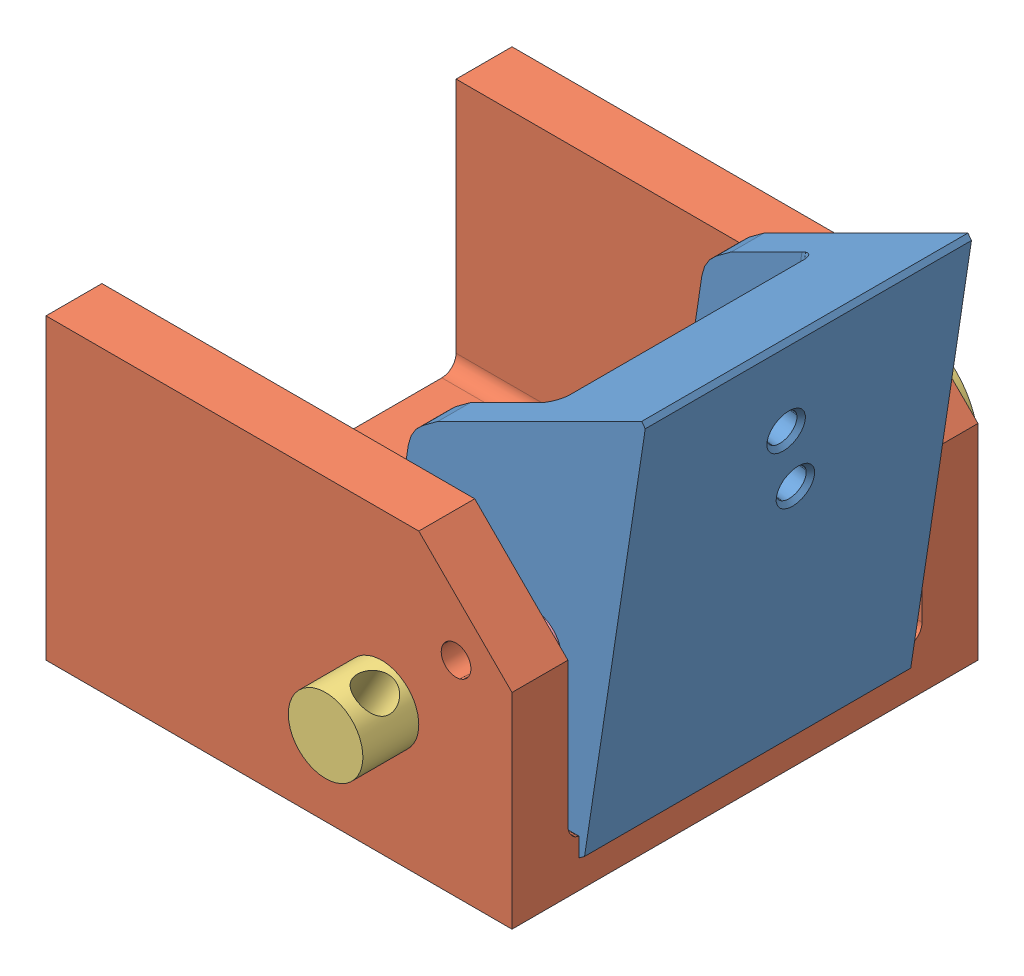
SolidWorks assembly Assem2, configuration Default. Lengths in mm.
Overall size (28.58 25.17 31).
7 component instances, 5 part files, 9 mates.
Components (placement in the parent):
- Swing piece better redesign v2-1: Swing piece better redesign v2 [Default] at (10.5166 16.001 11.8718) x (0.988728 -0.14972 0) z (0 0 1) size (11.5 22.34 17.5)
- Base better redesign-1: Base better redesign [Default] at (1.9122 2.865 20.4718) x (1 0 0) z (0 -1 0) size (25 25 16)
- Hinge mcmaster 4mm-1: Hinge mcmaster 4mm [93217A290] at (7.4122 7.365 129.9718) x (0.866515 -0.49915 0) z (0 0 1) size (8 8 31)
- Pin mcmaster_v2-1: Pin mcmaster_v2 [98378A149] at (11.966 10.7211 -18.0282) x (-0.894491 0.447087 0) z (0 0 -1) size (3 3 7)
- 9271K88_Torsion Spring-1: 9271K88_Torsion Spring [9271K88] at (7.691 7.499 23.983) x (0.159653 -0.022827 -0.986909) z (-0.95932 -0.239394 -0.149653) size (4.03 5.49 38.1) (hidden)
- 9271K88_Torsion Spring-3: 9271K88_Torsion Spring [9271K88] at (7.1421 7.2576 15.5875) x (-0.070231 -0.093274 -0.99316) z (-0.995192 0.074684 0.06336) size (4.03 5.49 38.1) (hidden)
- Pin mcmaster_v2-3: Pin mcmaster_v2 [98378A149] at (11.966 10.7211 58.9718) x (0.595621 -0.803266 0) z (0 0 1) size (3 3 7)
Mates (geometry in assembly coordinates):
- Concentric1: concentric anti-aligned: cylinder of Hinge mcmaster 4mm-1 through (7.4122 7.365 254.9718) axis (0 0 1) radius 2; cylinder of Base better redesign-1 through (7.4122 7.365 32.9718) axis (0 0 -1) radius 2
- Coincident2: coincident anti-aligned: plane of Base better redesign-1 through (-10.5878 0.365 7.9718) normal (0 0 -1); plane of Hinge mcmaster 4mm-1 through (9.4088 10.8311 7.9718) normal (0 0 1)
- Concentric2: concentric anti-aligned: cylinder of Swing piece better redesign v2-1 through (7.4122 7.365 29.3718) axis (0 0 -1) radius 2; cylinder of Hinge mcmaster 4mm-1 through (7.4122 7.365 254.9718) axis (0 0 1) radius 2
- Distance1: distance = 0.6 mm anti-aligned: plane of Swing piece better redesign v2-1 through (10.5166 16.001 29.3718) normal (0 0 1); plane of Base better redesign-1 through (-10.5878 16.365 29.9718) normal (0 0 -1)
- Concentric4: concentric anti-aligned: cylinder of Swing piece better redesign v2-1 through (11.966 10.7211 18.8718) axis (0 0 -1) radius 1.5; cylinder of Pin mcmaster_v2-1 through (11.966 10.7211 15.9718) axis (0 0 1) radius 1.5
- Coincident5: coincident anti-aligned: plane of Base better redesign-1 through (-10.5878 16.365 10.9718) normal (0 0 1); plane of Pin mcmaster_v2-1 through (12.413 11.6155 10.9718) normal (0 0 -1)
- Tangent6: tangent anti-aligned: cylinder of Hinge mcmaster 4mm-1 through (7.4122 7.365 254.9718) axis (0 0 1) radius 2; face of 9271K88_Torsion Spring-1
- Concentric6: concentric anti-aligned: cylinder of Swing piece better redesign v2-1 through (11.966 10.7211 22.3718) axis (0 0 1) radius 1.5; cylinder of Pin mcmaster_v2-3 through (11.966 10.7211 24.9718) axis (0 0 -1) radius 1.5
- Coincident6: coincident anti-aligned: plane of Base better redesign-1 through (-10.5878 16.365 29.9718) normal (0 0 -1); plane of Pin mcmaster_v2-3 through (12.7692 11.3167 29.9718) normal (0 0 1)
